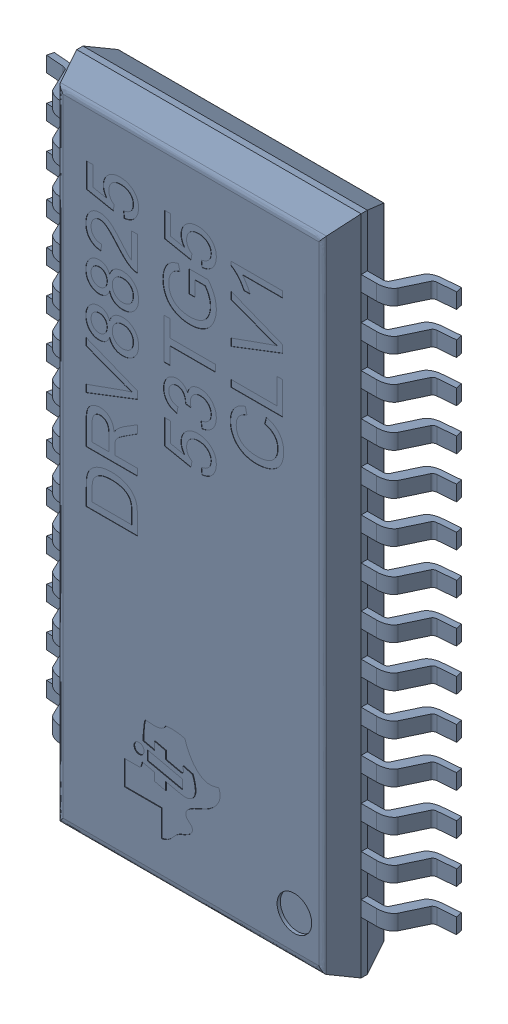
SolidWorks assembly DRV8825 Driver v9 (1), configuration Default. Lengths in mm.
Overall size (6.33 10.21 1.04).
2 component instances, 1 part files, 0 mates.
Components (placement in the parent):
- DRV8825 53TG5 CLV1 (1)-1: DRV8825 53TG5 CLV1 (1) [Default] at (6.5481 7.5317 9.8148) x (1 0 0) z (0 -1 0) size (6.33 1.04 10.21)
  - Package (1)-1: Package (1) [Default] at origin size (6.33 1.04 10.21)
